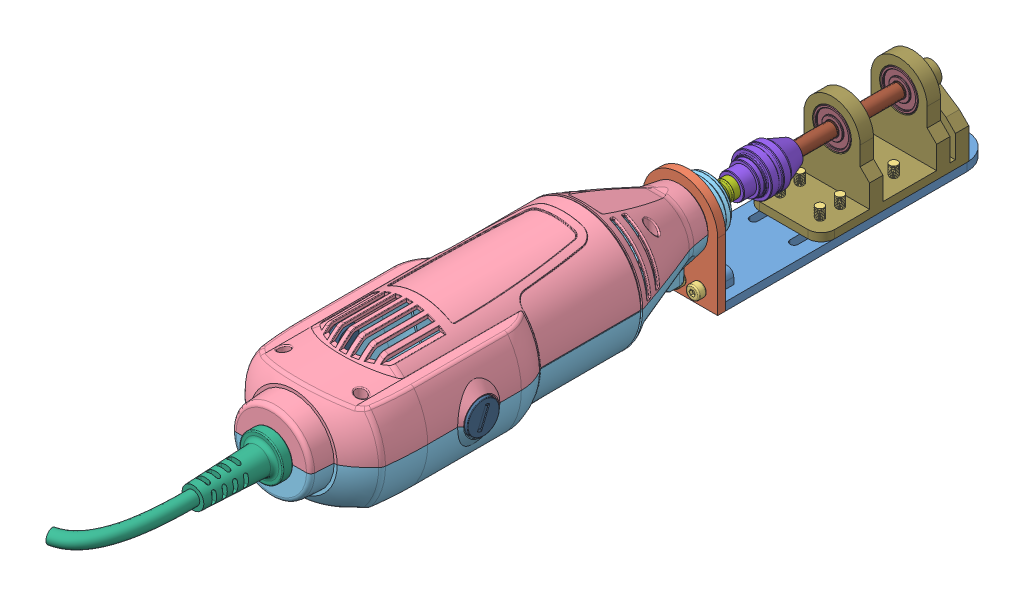
SolidWorks assembly Ensamblaje1, configuration Predeterminado. Lengths in mm.
Overall size (56.71 52.89 325.86).
24 component instances, 13 part files, 22 mates.
Components (placement in the parent):
- guia_2-1: guia_2 [Predeterminado] at (-1.4582 -5.4354 142.5) size (28 8 100)
- guia-1: guia [Predeterminado] at (-1.4582 19.5646 142.5) size (28 39 3)
- Tornillo M3x10_2-1: Tornillo M3x10_2 [Predeterminado] at (-8.9582 0.0646 135.5) size (5 5 13)
- Tornillo M3x10_2-2: Tornillo M3x10_2 [Predeterminado] at (-1.4582 0.0646 135.5) size (5 5 13)
- Tornillo M3x10_2-3: Tornillo M3x10_2 [Predeterminado] at (6.0418 0.0646 135.5) size (5 5 13)
- Dremel Assembly-1: Dremel Assembly [Default] at (-1.4582 19.5646 145.5) x (-1 0 0) z (0 0 -1) size (56.71 52.89 264.48)
  - Dremel Left Half-1: Dremel Left Half [Default] at origin size (55.12 24.36 152.4)
  - Dremel Right Half-1: Dremel Right Half [Default] x (-1 0 0) z (0 0 1) size (55.12 36.04 163.96)
  - Dremel Chord-1: Dremel Chord [Default] at (0 0 -144.4625) x (1 0 0) z (0 1 0) size (22.66 78.4 16.21)
  - Dremel Chuck Mount-1: Dremel Chuck Mount [Default] at (0 0 -7.9375) x (0.325874 -0.945413 0) z (-0.945413 -0.325874 0) size (8.71 38.1 8.71)
  - Dremel Chuck-1: Dremel Chuck [Default] at (0 0 19.0627) x (0.99596 -0.0898 0) z (-0.0898 -0.99596 0) size (15.24 22.56 15.24)
  - Dremel Speed Lever-1: Dremel Speed Lever [Default] at (0 0 -93.09) x (-0.965324 -0.261055 0) z (0 0 1) size (27.22 10.71 7.94)
  - Dremel Motor Adjust-1: Dremel Motor Adjust [Default] at (-22.0028 0 -101.6) x (0 0.384439 -0.92315) z (1 0 0) size (11.91 11.91 6.35)
  - Dremel Motor Adjust-2: Dremel Motor Adjust [Default] at (22.0028 0 -101.6) x (0 -0.384439 0.92315) z (-1 0 0) size (11.91 11.91 6.35)
- Eje p ruedas v3-1: Eje p ruedas v3 [Predeterminado] at (-1.5602 19.5646 71.6519) size (5 5 60)
- guia_3-1: guia_3 [Predeterminado] at (-1.4582 -2.4354 91.8821) x (0 0 -1) z (1 0 0) size (55 32.5 28)
- Ruleman 605-1: Ruleman 605 [Predeterminado] at (-1.4582 19.5646 83.8821) size (14 14 5)
- Ruleman 605-2: Ruleman 605 [Predeterminado] at (-1.4582 19.5646 58.8821) size (14 14 5)
- Tornillo M3x10_2-4: Tornillo M3x10_2 [Predeterminado] at (-8.9582 4.5646 100.8821) x (1 0 0) z (0 -1 0) size (5 5 13)
- Tornillo M3x10_2-5: Tornillo M3x10_2 [Predeterminado] at (-8.9582 4.5646 93.3821) x (1 0 0) z (0 -1 0) size (5 5 13)
- Tornillo M3x10_2-6: Tornillo M3x10_2 [Predeterminado] at (-8.9582 4.5646 73.3821) x (1 0 0) z (0 -1 0) size (5 5 13)
- Tornillo M3x10_2-8: Tornillo M3x10_2 [Predeterminado] at (6.0418 4.5646 93.3821) x (1 0 0) z (0 -1 0) size (5 5 13)
- Tornillo M3x10_2-9: Tornillo M3x10_2 [Predeterminado] at (6.0418 4.5646 73.3821) x (1 0 0) z (0 -1 0) size (5 5 13)
- Tornillo M3x10_2-10: Tornillo M3x10_2 [Predeterminado] at (6.0418 4.5646 100.8821) x (1 0 0) z (0 -1 0) size (5 5 13)
Mates (geometry in assembly coordinates):
- Coincidente1: coincident anti-aligned: plane of guia_2-1 through (-15.4582 -2.4354 142.5) normal (0 0 1); plane of guia-1 through (-1.4582 19.5646 142.5) normal (0 0 -1)
- Concéntrica1: concentric aligned: circle of guia_2-1; circle of guia-1
- CentroDePerfil1: profile center anti-aligned: circle of Tornillo M3x10_2-1; circle of guia-1
- CentroDePerfil2: profile center anti-aligned: circle of Tornillo M3x10_2-2; circle of guia-1
- CentroDePerfil3: profile center anti-aligned: circle of Tornillo M3x10_2-3; circle of guia-1
- Coincidente2: coincident anti-aligned: plane of guia-1 through (-1.4582 19.5646 145.5) normal (0 0 1); plane of Dremel Assembly-1/Dremel Left Half-1 through (-95.3339 19.5646 145.5) normal (0 0 -1)
- Concéntrica2: concentric anti-aligned: cylinder of guia-1 through (-1.4582 19.5646 145.5) axis (0 0 -1) radius 9.75; cylinder of Dremel Assembly-1/Dremel Right Half-1 through (-1.4582 19.5646 145.5) axis (0 0 1) radius 9.525
- Coincidente3: coincident anti-aligned: plane of Dremel Assembly-1/Dremel Chuck-1 through (-5.7587 19.1769 103.8821) normal (0 0 -1); plane of Eje p ruedas v3-1 through (0.5418 19.5646 103.8821) normal (0 0 1)
- Concéntrica3: concentric anti-aligned: cone of Dremel Assembly-1/Dremel Chuck-1 through (-1.4582 19.5646 103.8821) axis (0 0 -1); cylinder of Eje p ruedas v3-1 through (-1.4582 19.5646 56.8821) axis (0 0 1) radius 2.5
- Coincidente4: coincident anti-aligned: plane of guia_2-1 through (-1.4582 -2.4354 142.5) normal (0 1 0); plane of guia_3-1 through (-1.4582 -2.4354 91.8821) normal (0 -1 0)
- Coincidente5: coincident aligned: plane of guia_2-1 through (12.5418 -2.4354 142.5) normal (1 0 0); plane of guia_3-1 through (12.5418 0.5646 91.8821) normal (1 0 0)
- Distancia1: distance = 5 mm aligned: plane of guia_3-1 through (-15.4582 0.5646 51.8821) normal (0 0 -1); plane of Eje p ruedas v3-1 through (0.5418 19.5646 56.8821) normal (0 0 -1)
- Coincidente7: coincident aligned: plane of guia_3-1 through (12.5418 30.5646 83.8821) normal (0 0 -1); plane of Ruleman 605-1 through (-1.4582 19.5646 83.8821) normal (0 0 -1)
- Coincidente8: coincident aligned: plane of guia_3-1 through (12.5418 30.5646 58.8821) normal (0 0 -1); plane of Ruleman 605-2 through (-1.4582 19.5646 58.8821) normal (0 0 -1)
- Concéntrica4: concentric anti-aligned: cylinder of guia_3-1 through (-1.4582 19.5646 58.8821) axis (0 0 1) radius 7.25; cylinder of Ruleman 605-2 through (-1.4582 19.5646 63.8821) axis (0 0 -1) radius 7
- Concéntrica5: concentric anti-aligned: cylinder of guia_3-1 through (-1.4582 19.5646 58.8821) axis (0 0 1) radius 7.25; cylinder of Ruleman 605-1 through (-1.4582 19.5646 88.8821) axis (0 0 -1) radius 7
- Coincidente9: coincident anti-aligned: plane of guia_2-1 through (-1.4582 -5.4354 142.5) normal (0 -1 0); plane of Tornillo M3x10_2-4 through (-8.9582 -5.4354 100.8821) normal (0 1 0)
- Coincidente10: coincident anti-aligned: plane of guia_2-1 through (-1.4582 -5.4354 142.5) normal (0 -1 0); plane of Tornillo M3x10_2-5 through (-8.9582 -5.4354 93.3821) normal (0 1 0)
- Coincidente11: coincident anti-aligned: plane of guia_2-1 through (-1.4582 -5.4354 142.5) normal (0 -1 0); plane of Tornillo M3x10_2-6 through (-8.9582 -5.4354 73.3821) normal (0 1 0)
- Concéntrica6: concentric anti-aligned: cylinder of guia_3-1 through (-8.9582 30.0656 100.8821) axis (0 -1 0) radius 1.25; cylinder of Tornillo M3x10_2-4 through (-8.9582 -8.4354 100.8821) axis (0 1 0) radius 2.5
- Concéntrica7: concentric anti-aligned: cylinder of guia_3-1 through (-8.9582 30.0656 93.3821) axis (0 -1 0) radius 1.25; cylinder of Tornillo M3x10_2-5 through (-8.9582 -8.4354 93.3821) axis (0 1 0) radius 2.5
- Concéntrica8: concentric anti-aligned: cylinder of guia_3-1 through (-8.9582 30.0656 73.3821) axis (0 -1 0) radius 1.25; cylinder of Tornillo M3x10_2-6 through (-8.9582 -8.4354 73.3821) axis (0 1 0) radius 2.5
